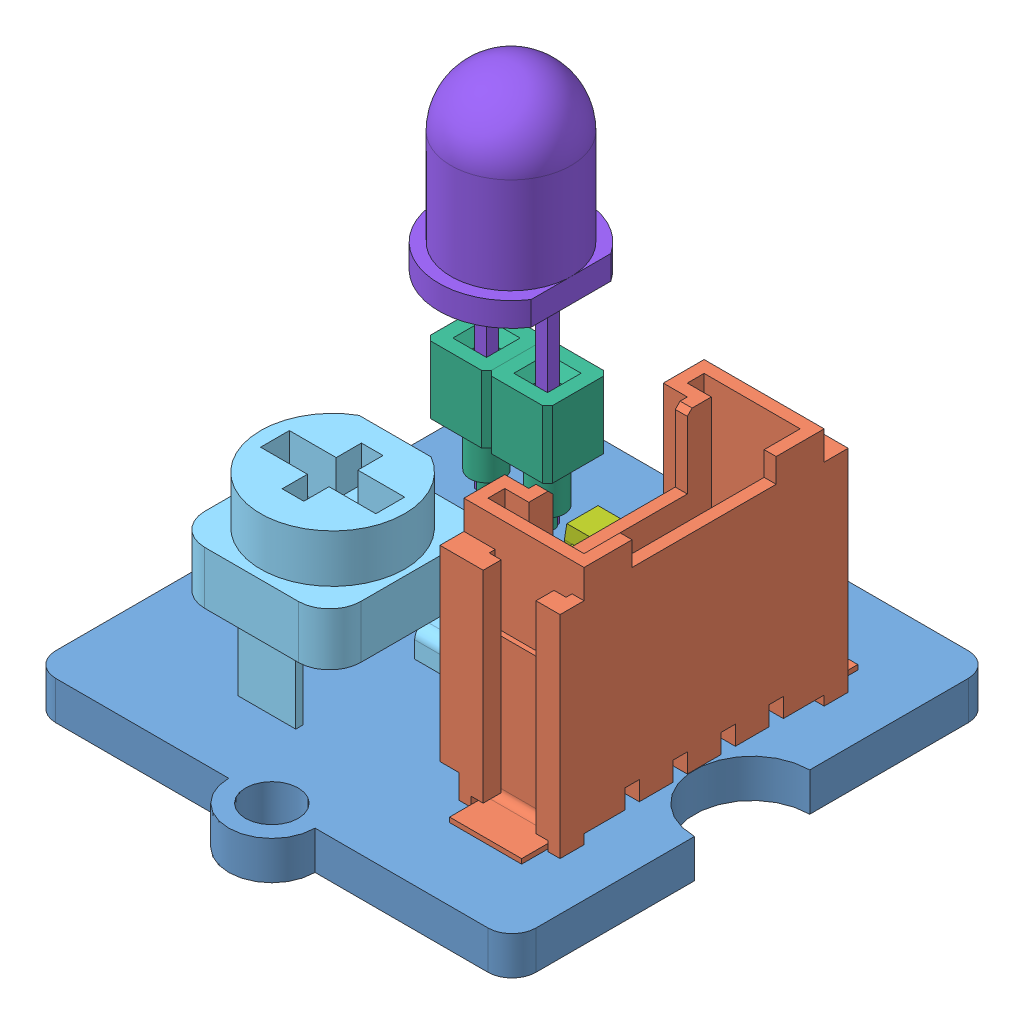
SolidWorks assembly Grove LED verte, configuration Défaut. Lengths in mm.
Overall size (20 19.1 23.6).
11 component instances, 8 part files, 16 mates.
Components (placement in the parent):
- PCB grove 20x20-1: PCB grove 20x20 [Défaut] at (7.4555 -4.1841 0) size (20 1.6 23.6)
- Connecteur Grove (droit CMS)-1: Connecteur Grove (droit CMS) [Défaut] at (10.4555 -2.5841 0) x (-1 0 0) z (0 1 0) size (6.5 14 10)
- 603 resistor 102-2: 603 resistor 102 [Default] at (3.6365 -2.5841 -1.49) size (2.36 0.62 1.03)
- 603 cap on pad-1: 603 cap on pad [Défaut] at (8.4655 -2.5841 -6.62) x (0 0 1) z (-1 0 0) size (2.76 0.91 1.12)
- 603 resistor 102-3: 603 resistor 102 [Default] at (6.6365 -2.5841 -1.49) size (2.36 0.62 1.03)
- 603 resistor 102-4: 603 resistor 102 [Default] at (6.6365 -2.5841 -2.99) size (2.36 0.62 1.03)
- Pot - RES_VAR1-1: Pot - RES_VAR1 [Défaut] at (4.0824 2.7159 4.0972) size (6.5 10.5 7.06)
- Contact F-1: Contact F [Défaut] at (0.621 0.0871 -5.7728) size (2.54 7.5 2.54)
- ssot3-1: ssot3 [Default] at (6.0932 -2.5841 -5.7439) size (3 1.13 3.09)
- LED 5mm Verte-3: LED 5mm Verte [Default] at (1.591 5.8159 -5.8228) x (1 0 0) z (0 1 0) size (5.5 6 17.5)
- Contact F-2: Contact F [Défaut] at (3.161 0.0871 -5.7728) size (2.54 7.5 2.54)
Mates (geometry in assembly coordinates):
- Distance1: distance = 2 mm aligned: plane of PCB grove 20x20-1 through (17.4555 -2.5841 0) normal (1 0 0); plane of Connecteur Grove (droit CMS)-1 through (15.4555 7.4159 6) normal (1 0 0)
- Distance2: distance = 4 mm aligned: plane of Connecteur Grove (droit CMS)-1 through (14.4555 7.4159 -6) normal (0 0 -1); plane of PCB grove 20x20-1 through (7.4555 -2.5841 -10) normal (0 0 -1)
- Coïncidente16: coincident anti-aligned: plane of PCB grove 20x20-1 through (7.4555 -2.5841 0) normal (0 1 0); plane of 603 resistor 102-2 through (3.6365 -2.5841 -1.49) normal (0 -1 0)
- Distance12: distance = 8 mm: plane of PCB grove 20x20-1 through (7.4555 -2.5841 -10) normal (0 0 -1); line of 603 resistor 102-2 through (4.8175 -2.5841 -2) axis (-1 0 0)
- Distance13: distance = 5 mm: line of 603 resistor 102-2 through (2.4555 -2.5841 -2) axis (0 0 1); plane of PCB grove 20x20-1 through (-2.5445 -2.5841 0) normal (-1 0 0)
- Coïncidente24: coincident anti-aligned: plane of PCB grove 20x20-1 through (7.4555 -2.5841 0) normal (0 1 0); plane of 603 cap on pad-1 through (8.4655 -2.5841 -6.62) normal (0 -1 0)
- Distance17: distance = 10.5 mm: line of PCB grove 20x20-1 through (-2.5445 -2.5841 9) axis (0 0 -1); line of 603 cap on pad-1 through (7.9555 -2.5841 -5.24) axis (0 0 -1)
- Distance18: distance = 2 mm: line of PCB grove 20x20-1 through (-1.5445 -2.5841 -10) axis (1 0 0); line of 603 cap on pad-1 through (7.9555 -2.5841 -8) axis (1 0 0)
- Verrouiller1: lock: unknown of PCB grove 20x20-1; unknown of ?
- Verrouiller2: lock: unknown of PCB grove 20x20-1; unknown of ?
- Verrouiller3: lock: unknown of PCB grove 20x20-1; unknown of ?
- Coïncidente30: coincident anti-aligned: plane of PCB grove 20x20-1 through (7.4555 -2.5841 0) normal (0 1 0); plane of ssot3-1 through (6.0932 -2.5841 -5.7439) normal (0 -1 0)
- Coïncidente31: coincident anti-aligned: plane of Contact F-2 through (2.861 2.8871 -6.0728) normal (0 0 1); plane of LED 5mm Verte-3 through (1.591 5.8159 -6.0728) normal (0 0 -1)
- Coïncidente32: coincident anti-aligned: plane of Contact F-1 through (0.321 2.8871 -5.4728) normal (1 0 0); plane of LED 5mm Verte-3 through (0.321 5.8159 -6.0728) normal (-1 0 0)
- Coïncidente33: coincident aligned: plane of PCB grove 20x20-1 through (7.4555 -4.1841 0) normal (0 -1 0); plane of LED 5mm Verte-3 through (0.321 -4.1841 -6.0728) normal (0 -1 0)
- Coïncidente34: coincident anti-aligned: plane of PCB grove 20x20-1 through (7.4555 -2.5841 0) normal (0 1 0); plane of Connecteur Grove (droit CMS)-1 through (10.4555 -2.5841 0) normal (0 -1 0)
